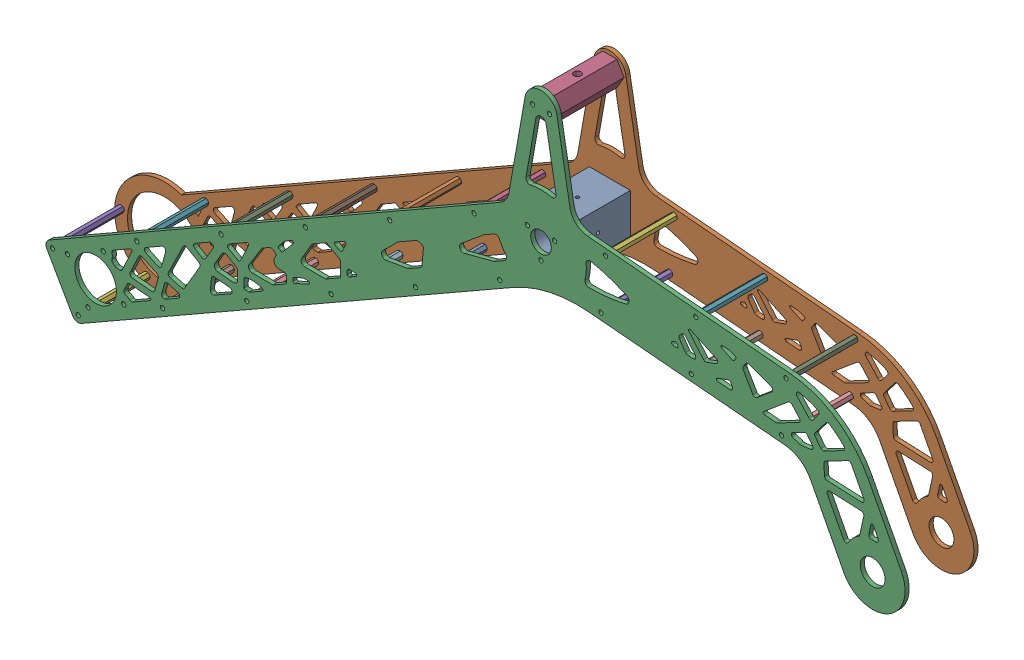
SolidWorks assembly Right Rocker Assy-2023, configuration Default. Lengths in mm.
Overall size (663.55 336.79 56.35).
22 component instances, 5 part files, 84 mates.
Components (placement in the parent):
- Rocker Adapter-2023-1: Rocker Adapter-2023 [Default] at origin size (31.75 31.75 50)
- Rocker Plate - Inner-2023-1: Rocker Plate - Inner-2023 [Default] at (0 0 -28.175) size (663.55 336.79 3.17)
- Rocker Plate - Outer-2023-1: Rocker Plate - Outer-2023 [Default] at (0 0 25) size (663.31 333.98 3.17)
- Differential Adapter-2023-1: Differential Adapter-2023 [Default] at (0 88.9125 0) size (21.94 19 50)
- Standoff Nut-2023-1: Standoff Nut-2023 [95947A502] at (-377.2333 -192.8465 -25) x (0 0 1) z (-1 0 0) size (50 4.5 5.2)
- Standoff Nut-2023-2: Standoff Nut-2023 [95947A502] at (-357.3649 -227.5632 -25) x (0 0 1) z (-0.987351 -0.158553 0) size (50 4.5 5.2)
- Standoff Nut-2023-3: Standoff Nut-2023 [95947A502] at (-312.1394 -155.5934 -25) x (0 0 1) z (-0.959125 -0.282984 0) size (50 4.5 5.2)
- Standoff Nut-2023-4: Standoff Nut-2023 [95947A502] at (-292.2711 -190.3101 -25) x (0 0 1) z (-0.928571 -0.371154 0) size (50 4.5 5.2)
- Standoff Nut-2023-5: Standoff Nut-2023 [95947A502] at (-247.0456 -118.3403 -25) x (0 0 1) z (-0.906989 -0.421154 0) size (50 4.5 5.2)
- Standoff Nut-2023-6: Standoff Nut-2023 [95947A502] at (-227.1773 -153.057 -25) x (0 0 1) z (-0.902849 -0.429957 0) size (50 4.5 5.2)
- Standoff Nut-2023-7: Standoff Nut-2023 [95947A502] at (-181.9518 -81.0871 -25) x (0 0 1) z (-0.919615 -0.39282 0) size (50 4.5 5.2)
- Standoff Nut-2023-8: Standoff Nut-2023 [95947A502] at (-162.0835 -115.8038 -25) x (0 0 1) z (-0.952324 -0.305088 0) size (50 4.5 5.2)
- Standoff Nut-2023-9: Standoff Nut-2023 [95947A502] at (-96.9897 -78.5507 -25) x (0 0 1) z (-0.985697 -0.168526 0) size (50 4.5 5.2)
- Standoff Nut-2023-10: Standoff Nut-2023 [95947A502] at (-116.858 -43.834 -25) x (0 0 1) z (-1 0 0) size (50 4.5 5.2)
- Standoff Nut-2023-11: Standoff Nut-2023 [95947A502] at (-31.8958 -41.2976 -25) x (0 0 1) z (-0.985697 0.168526 0) size (50 4.5 5.2)
- Standoff Nut-2023-12: Standoff Nut-2023 [95947A502] at (-51.7642 -6.5809 -25) x (0 0 1) z (-0.952324 0.305088 0) size (50 4.5 5.2)
- Standoff Nut-2023-13: Standoff Nut-2023 [95947A502] at (46.2693 -24.1244 -25) x (0 0 1) z (-0.919615 0.39282 0) size (50 4.5 5.2)
- Standoff Nut-2023-14: Standoff Nut-2023 [95947A502] at (49.7555 15.7234 -25) x (0 0 1) z (-0.902849 0.429957 0) size (50 4.5 5.2)
- Standoff Nut-2023-15: Standoff Nut-2023 [95947A502] at (119.4892 9.6224 -25) x (0 0 1) z (-0.906989 0.421154 0) size (50 4.5 5.2)
- Standoff Nut-2023-16: Standoff Nut-2023 [95947A502] at (116.0029 -30.2253 -25) x (0 0 1) z (-0.928571 0.371154 0) size (50 4.5 5.2)
- Standoff Nut-2023-17: Standoff Nut-2023 [95947A502] at (189.2228 3.5215 -25) x (0 0 1) z (-0.959125 0.282984 0) size (50 4.5 5.2)
- Standoff Nut-2023-18: Standoff Nut-2023 [95947A502] at (185.7366 -36.3262 -25) x (0 0 1) z (-0.987351 0.158553 0) size (50 4.5 5.2)
Mates (geometry in assembly coordinates):
- Concentric1: concentric anti-aligned: cylinder of Rocker Adapter-1 through (0 -12.1244 25) axis (0 0 -1) radius 1.25; cylinder of Rocker Plate - Inner-1 through (0 -12.1244 -28.175) axis (0 0 1) radius 1.65
- Concentric2: concentric anti-aligned: cylinder of Rocker Adapter-1 through (10.5 6.0622 25) axis (0 0 -1) radius 1.25; cylinder of Rocker Plate - Inner-1 through (10.5 6.0622 -28.175) axis (0 0 1) radius 1.65
- Coincident1: coincident anti-aligned: plane of Rocker Adapter-1 through (0 0 25) normal (0 0 1); plane of Rocker Plate - Outer-1 through (37.0941 36.9075 25) normal (0 0 -1)
- Concentric3: concentric anti-aligned: cylinder of Rocker Adapter-1 through (0 -12.1244 25) axis (0 0 -1) radius 1.25; cylinder of Rocker Plate - Outer-1 through (0 -12.1244 25) axis (0 0 1) radius 1.65
- Concentric4: concentric anti-aligned: cylinder of Rocker Adapter-1 through (-10.5 6.0622 25) axis (0 0 -1) radius 1.25; cylinder of Rocker Plate - Outer-1 through (-10.5 6.0622 25) axis (0 0 1) radius 1.65
- Coincident2: coincident anti-aligned: plane of Rocker Adapter-1 through (0 0 -25) normal (0 0 -1); plane of Rocker Plate - Inner-1 through (37.0941 36.9075 -25) normal (0 0 1)
- Concentric5: concentric aligned: cylinder of Rocker Plate - Outer-1 through (-6.5 88.9125 28.175) axis (0 0 -1) radius 1.65; cylinder of Differential Adapter-1 through (-6.5 88.9125 25) axis (0 0 -1) radius 1.25
- Concentric6: concentric aligned: cylinder of Rocker Plate - Outer-1 through (6.5 88.9125 28.175) axis (0 0 -1) radius 1.65; cylinder of Differential Adapter-1 through (6.5 88.9125 25) axis (0 0 -1) radius 1.25
- Concentric7: concentric aligned: cylinder of Rocker Plate - Inner-1 through (-6.5 88.9125 -25) axis (0 0 -1) radius 1.65; cylinder of Differential Adapter-1 through (-6.5 88.9125 25) axis (0 0 -1) radius 1.25
- Concentric8: concentric aligned: cylinder of Rocker Plate - Inner-1 through (6.5 88.9125 -25) axis (0 0 -1) radius 1.65; cylinder of Differential Adapter-1 through (6.5 88.9125 25) axis (0 0 -1) radius 1.25
- Coincident3: coincident anti-aligned: plane of Rocker Plate - Outer-1 through (37.0941 36.9075 25) normal (0 0 -1); plane of Differential Adapter-1 through (0 88.9125 25) normal (0 0 1)
- Coincident4: coincident anti-aligned: plane of Rocker Plate - Inner-1 through (37.0941 36.9075 -25) normal (0 0 1); plane of Differential Adapter-1 through (0 88.9125 -25) normal (0 0 -1)
- Concentric9: concentric anti-aligned: cylinder of Rocker Plate - Outer-1 through (-377.2333 -192.8465 25) axis (0 0 1) radius 1.65; cylinder of Standoff Nut-1 through (-377.2333 -192.8465 -25) axis (0 0 -1) radius 1.5
- Concentric10: concentric anti-aligned: cylinder of Rocker Plate - Inner-1 through (-377.2333 -192.8465 -28.175) axis (0 0 1) radius 1.65; cylinder of Standoff Nut-1 through (-377.2333 -192.8465 -25) axis (0 0 -1) radius 1.5
- Coincident5: coincident anti-aligned: plane of Rocker Plate - Outer-1 through (37.0941 36.9075 25) normal (0 0 -1); plane of Standoff Nut-1 through (-377.2333 -192.8465 25) normal (0 0 1)
- Coincident6: coincident anti-aligned: plane of Rocker Plate - Inner-1 through (37.0941 36.9075 -25) normal (0 0 1); plane of Standoff Nut-1 through (-377.2333 -192.8465 -25) normal (0 0 -1)
- Coincident7: coincident anti-aligned: plane of Rocker Plate - Outer-1 through (37.0941 36.9075 25) normal (0 0 -1); plane of Standoff Nut-2 through (-357.3649 -227.5632 25) normal (0 0 1)
- Coincident8: coincident anti-aligned: plane of Rocker Plate - Inner-1 through (37.0941 36.9075 -25) normal (0 0 1); plane of Standoff Nut-2 through (-357.3649 -227.5632 -25) normal (0 0 -1)
- Concentric11: concentric anti-aligned: cylinder of Rocker Plate - Outer-1 through (-357.3649 -227.5632 25) axis (0 0 1) radius 1.65; cylinder of Standoff Nut-2 through (-357.3649 -227.5632 -25) axis (0 0 -1) radius 1.5
- Concentric12: concentric anti-aligned: cylinder of Rocker Plate - Inner-1 through (-357.3649 -227.5632 -28.175) axis (0 0 1) radius 1.65; cylinder of Standoff Nut-2 through (-357.3649 -227.5632 -25) axis (0 0 -1) radius 1.5
- Coincident9: coincident anti-aligned: plane of Rocker Plate - Outer-1 through (37.0941 36.9075 25) normal (0 0 -1); plane of Standoff Nut-3 through (-312.1394 -155.5934 25) normal (0 0 1)
- Coincident10: coincident anti-aligned: plane of Rocker Plate - Inner-1 through (37.0941 36.9075 -25) normal (0 0 1); plane of Standoff Nut-3 through (-312.1394 -155.5934 -25) normal (0 0 -1)
- Concentric14: concentric anti-aligned: cylinder of Rocker Plate - Outer-1 through (-312.1394 -155.5934 25) axis (0 0 1) radius 1.65; cylinder of Standoff Nut-3 through (-312.1394 -155.5934 -25) axis (0 0 -1) radius 1.5
- Concentric15: concentric anti-aligned: cylinder of Rocker Plate - Inner-1 through (-312.1394 -155.5934 -28.175) axis (0 0 1) radius 1.65; cylinder of Standoff Nut-3 through (-312.1394 -155.5934 -25) axis (0 0 -1) radius 1.5
- Coincident11: coincident anti-aligned: plane of Rocker Plate - Outer-1 through (37.0941 36.9075 25) normal (0 0 -1); plane of Standoff Nut-4 through (-292.2711 -190.3101 25) normal (0 0 1)
- Coincident12: coincident anti-aligned: plane of Rocker Plate - Inner-1 through (37.0941 36.9075 -25) normal (0 0 1); plane of Standoff Nut-4 through (-292.2711 -190.3101 -25) normal (0 0 -1)
- Concentric16: concentric anti-aligned: cylinder of Rocker Plate - Outer-1 through (-292.2711 -190.3101 25) axis (0 0 1) radius 1.65; cylinder of Standoff Nut-4 through (-292.2711 -190.3101 -25) axis (0 0 -1) radius 1.5
- Concentric17: concentric anti-aligned: cylinder of Rocker Plate - Inner-1 through (-292.2711 -190.3101 -28.175) axis (0 0 1) radius 1.65; cylinder of Standoff Nut-4 through (-292.2711 -190.3101 -25) axis (0 0 -1) radius 1.5
- Coincident13: coincident anti-aligned: plane of Rocker Plate - Outer-1 through (37.0941 36.9075 25) normal (0 0 -1); plane of Standoff Nut-5 through (-247.0456 -118.3403 25) normal (0 0 1)
- Coincident14: coincident anti-aligned: plane of Rocker Plate - Inner-1 through (37.0941 36.9075 -25) normal (0 0 1); plane of Standoff Nut-5 through (-247.0456 -118.3403 -25) normal (0 0 -1)
- Concentric18: concentric anti-aligned: cylinder of Rocker Plate - Outer-1 through (-247.0456 -118.3403 25) axis (0 0 1) radius 1.65; cylinder of Standoff Nut-5 through (-247.0456 -118.3403 -25) axis (0 0 -1) radius 1.5
- Concentric19: concentric anti-aligned: cylinder of Rocker Plate - Inner-1 through (-247.0456 -118.3403 -28.175) axis (0 0 1) radius 1.65; cylinder of Standoff Nut-5 through (-247.0456 -118.3403 -25) axis (0 0 -1) radius 1.5
- Coincident15: coincident anti-aligned: plane of Rocker Plate - Outer-1 through (37.0941 36.9075 25) normal (0 0 -1); plane of Standoff Nut-6 through (-227.1773 -153.057 25) normal (0 0 1)
- Coincident16: coincident anti-aligned: plane of Rocker Plate - Inner-1 through (37.0941 36.9075 -25) normal (0 0 1); plane of Standoff Nut-6 through (-227.1773 -153.057 -25) normal (0 0 -1)
- Concentric20: concentric anti-aligned: cylinder of Rocker Plate - Outer-1 through (-227.1773 -153.057 25) axis (0 0 1) radius 1.65; cylinder of Standoff Nut-6 through (-227.1773 -153.057 -25) axis (0 0 -1) radius 1.5
- Concentric21: concentric anti-aligned: cylinder of Rocker Plate - Inner-1 through (-227.1773 -153.057 -28.175) axis (0 0 1) radius 1.65; cylinder of Standoff Nut-6 through (-227.1773 -153.057 -25) axis (0 0 -1) radius 1.5
- Coincident17: coincident anti-aligned: plane of Rocker Plate - Outer-1 through (37.0941 36.9075 25) normal (0 0 -1); plane of Standoff Nut-7 through (-181.9518 -81.0871 25) normal (0 0 1)
- Coincident18: coincident anti-aligned: plane of Rocker Plate - Inner-1 through (37.0941 36.9075 -25) normal (0 0 1); plane of Standoff Nut-7 through (-181.9518 -81.0871 -25) normal (0 0 -1)
- Concentric22: concentric anti-aligned: cylinder of Rocker Plate - Outer-1 through (-181.9518 -81.0871 25) axis (0 0 1) radius 1.65; cylinder of Standoff Nut-7 through (-181.9518 -81.0871 -25) axis (0 0 -1) radius 1.5
- Concentric23: concentric anti-aligned: cylinder of Rocker Plate - Inner-1 through (-181.9518 -81.0871 -28.175) axis (0 0 1) radius 1.65; cylinder of Standoff Nut-7 through (-181.9518 -81.0871 -25) axis (0 0 -1) radius 1.5
- Coincident19: coincident anti-aligned: plane of Rocker Plate - Outer-1 through (37.0941 36.9075 25) normal (0 0 -1); plane of Standoff Nut-8 through (-162.0835 -115.8038 25) normal (0 0 1)
- Coincident20: coincident anti-aligned: plane of Rocker Plate - Inner-1 through (37.0941 36.9075 -25) normal (0 0 1); plane of Standoff Nut-8 through (-162.0835 -115.8038 -25) normal (0 0 -1)
- Concentric24: concentric anti-aligned: cylinder of Rocker Plate - Outer-1 through (-162.0835 -115.8038 25) axis (0 0 1) radius 1.65; cylinder of Standoff Nut-8 through (-162.0835 -115.8038 -25) axis (0 0 -1) radius 1.5
- Concentric25: concentric anti-aligned: cylinder of Rocker Plate - Inner-1 through (-162.0835 -115.8038 -28.175) axis (0 0 1) radius 1.65; cylinder of Standoff Nut-8 through (-162.0835 -115.8038 -25) axis (0 0 -1) radius 1.5
- Coincident21: coincident anti-aligned: plane of Rocker Plate - Outer-1 through (37.0941 36.9075 25) normal (0 0 -1); plane of Standoff Nut-9 through (-96.9897 -78.5507 25) normal (0 0 1)
- Coincident22: coincident anti-aligned: plane of Rocker Plate - Inner-1 through (37.0941 36.9075 -25) normal (0 0 1); plane of Standoff Nut-9 through (-96.9897 -78.5507 -25) normal (0 0 -1)
- Concentric26: concentric anti-aligned: cylinder of Rocker Plate - Outer-1 through (-96.9897 -78.5507 25) axis (0 0 1) radius 1.65; cylinder of Standoff Nut-9 through (-96.9897 -78.5507 -25) axis (0 0 -1) radius 1.5
- Concentric27: concentric anti-aligned: cylinder of Rocker Plate - Inner-1 through (-96.9897 -78.5507 -28.175) axis (0 0 1) radius 1.65; cylinder of Standoff Nut-9 through (-96.9897 -78.5507 -25) axis (0 0 -1) radius 1.5
- Coincident23: coincident anti-aligned: plane of Rocker Plate - Outer-1 through (37.0941 36.9075 25) normal (0 0 -1); plane of Standoff Nut-10 through (-116.858 -43.834 25) normal (0 0 1)
- Coincident24: coincident anti-aligned: plane of Rocker Plate - Inner-1 through (37.0941 36.9075 -25) normal (0 0 1); plane of Standoff Nut-10 through (-116.858 -43.834 -25) normal (0 0 -1)
- Concentric28: concentric anti-aligned: cylinder of Rocker Plate - Outer-1 through (-116.858 -43.834 25) axis (0 0 1) radius 1.65; cylinder of Standoff Nut-10 through (-116.858 -43.834 -25) axis (0 0 -1) radius 1.5
- Concentric29: concentric anti-aligned: cylinder of Rocker Plate - Inner-1 through (-116.858 -43.834 -28.175) axis (0 0 1) radius 1.65; cylinder of Standoff Nut-10 through (-116.858 -43.834 -25) axis (0 0 -1) radius 1.5
- Coincident25: coincident anti-aligned: plane of Rocker Plate - Outer-1 through (37.0941 36.9075 25) normal (0 0 -1); plane of Standoff Nut-11 through (-31.8958 -41.2976 25) normal (0 0 1)
- Coincident26: coincident anti-aligned: plane of Rocker Plate - Inner-1 through (37.0941 36.9075 -25) normal (0 0 1); plane of Standoff Nut-11 through (-31.8958 -41.2976 -25) normal (0 0 -1)
- Concentric30: concentric anti-aligned: cylinder of Rocker Plate - Outer-1 through (-31.8958 -41.2976 25) axis (0 0 1) radius 1.65; cylinder of Standoff Nut-11 through (-31.8958 -41.2976 -25) axis (0 0 -1) radius 1.5
- Concentric31: concentric anti-aligned: cylinder of Rocker Plate - Inner-1 through (-31.8958 -41.2976 -28.175) axis (0 0 1) radius 1.65; cylinder of Standoff Nut-11 through (-31.8958 -41.2976 -25) axis (0 0 -1) radius 1.5
- Coincident27: coincident anti-aligned: plane of Rocker Plate - Outer-1 through (37.0941 36.9075 25) normal (0 0 -1); plane of Standoff Nut-12 through (-51.7642 -6.5809 25) normal (0 0 1)
- Coincident28: coincident anti-aligned: plane of Rocker Plate - Inner-1 through (37.0941 36.9075 -25) normal (0 0 1); plane of Standoff Nut-12 through (-51.7642 -6.5809 -25) normal (0 0 -1)
- Concentric32: concentric anti-aligned: cylinder of Rocker Plate - Outer-1 through (-51.7642 -6.5809 25) axis (0 0 1) radius 1.65; cylinder of Standoff Nut-12 through (-51.7642 -6.5809 -25) axis (0 0 -1) radius 1.5
- Concentric33: concentric anti-aligned: cylinder of Rocker Plate - Inner-1 through (-51.7642 -6.5809 -28.175) axis (0 0 1) radius 1.65; cylinder of Standoff Nut-12 through (-51.7642 -6.5809 -25) axis (0 0 -1) radius 1.5
- Coincident29: coincident anti-aligned: plane of Rocker Plate - Outer-1 through (37.0941 36.9075 25) normal (0 0 -1); plane of Standoff Nut-13 through (46.2693 -24.1244 25) normal (0 0 1)
- Coincident30: coincident anti-aligned: plane of Rocker Plate - Inner-1 through (37.0941 36.9075 -25) normal (0 0 1); plane of Standoff Nut-13 through (46.2693 -24.1244 -25) normal (0 0 -1)
- Concentric34: concentric anti-aligned: cylinder of Rocker Plate - Outer-1 through (46.2693 -24.1244 25) axis (0 0 1) radius 1.65; cylinder of Standoff Nut-13 through (46.2693 -24.1244 -25) axis (0 0 -1) radius 1.5
- Concentric35: concentric anti-aligned: cylinder of Rocker Plate - Inner-1 through (46.2693 -24.1244 -28.175) axis (0 0 1) radius 1.65; cylinder of Standoff Nut-13 through (46.2693 -24.1244 -25) axis (0 0 -1) radius 1.5
- Coincident31: coincident anti-aligned: plane of Rocker Plate - Outer-1 through (37.0941 36.9075 25) normal (0 0 -1); plane of Standoff Nut-14 through (49.7555 15.7234 25) normal (0 0 1)
- Coincident32: coincident anti-aligned: plane of Rocker Plate - Inner-1 through (37.0941 36.9075 -25) normal (0 0 1); plane of Standoff Nut-14 through (49.7555 15.7234 -25) normal (0 0 -1)
- Concentric36: concentric anti-aligned: cylinder of Rocker Plate - Outer-1 through (49.7555 15.7234 25) axis (0 0 1) radius 1.65; cylinder of Standoff Nut-14 through (49.7555 15.7234 -25) axis (0 0 -1) radius 1.5
- Concentric37: concentric anti-aligned: cylinder of Rocker Plate - Inner-1 through (49.7555 15.7234 -28.175) axis (0 0 1) radius 1.65; cylinder of Standoff Nut-14 through (49.7555 15.7234 -25) axis (0 0 -1) radius 1.5
- Coincident33: coincident anti-aligned: plane of Rocker Plate - Outer-1 through (37.0941 36.9075 25) normal (0 0 -1); plane of Standoff Nut-15 through (119.4892 9.6224 25) normal (0 0 1)
- Coincident34: coincident anti-aligned: plane of Rocker Plate - Inner-1 through (37.0941 36.9075 -25) normal (0 0 1); plane of Standoff Nut-15 through (119.4892 9.6224 -25) normal (0 0 -1)
- Concentric38: concentric anti-aligned: cylinder of Rocker Plate - Outer-1 through (119.4892 9.6224 25) axis (0 0 1) radius 1.65; cylinder of Standoff Nut-15 through (119.4892 9.6224 -25) axis (0 0 -1) radius 1.5
- Concentric39: concentric anti-aligned: cylinder of Rocker Plate - Inner-1 through (119.4892 9.6224 -28.175) axis (0 0 1) radius 1.65; cylinder of Standoff Nut-15 through (119.4892 9.6224 -25) axis (0 0 -1) radius 1.5
- Coincident35: coincident anti-aligned: plane of Rocker Plate - Outer-1 through (37.0941 36.9075 25) normal (0 0 -1); plane of Standoff Nut-16 through (116.0029 -30.2253 25) normal (0 0 1)
- Coincident36: coincident anti-aligned: plane of Rocker Plate - Inner-1 through (37.0941 36.9075 -25) normal (0 0 1); plane of Standoff Nut-16 through (116.0029 -30.2253 -25) normal (0 0 -1)
- Concentric40: concentric anti-aligned: cylinder of Rocker Plate - Outer-1 through (116.0029 -30.2253 25) axis (0 0 1) radius 1.65; cylinder of Standoff Nut-16 through (116.0029 -30.2253 -25) axis (0 0 -1) radius 1.5
- Concentric41: concentric anti-aligned: cylinder of Rocker Plate - Inner-1 through (116.0029 -30.2253 -28.175) axis (0 0 1) radius 1.65; cylinder of Standoff Nut-16 through (116.0029 -30.2253 -25) axis (0 0 -1) radius 1.5
- Coincident37: coincident anti-aligned: plane of Rocker Plate - Outer-1 through (37.0941 36.9075 25) normal (0 0 -1); plane of Standoff Nut-17 through (189.2228 3.5215 25) normal (0 0 1)
- Coincident38: coincident anti-aligned: plane of Rocker Plate - Inner-1 through (37.0941 36.9075 -25) normal (0 0 1); plane of Standoff Nut-17 through (189.2228 3.5215 -25) normal (0 0 -1)
- Concentric42: concentric anti-aligned: cylinder of Rocker Plate - Outer-1 through (189.2228 3.5215 25) axis (0 0 1) radius 1.65; cylinder of Standoff Nut-17 through (189.2228 3.5215 -25) axis (0 0 -1) radius 1.5
- Concentric43: concentric anti-aligned: cylinder of Rocker Plate - Inner-1 through (189.2228 3.5215 -28.175) axis (0 0 1) radius 1.65; cylinder of Standoff Nut-17 through (189.2228 3.5215 -25) axis (0 0 -1) radius 1.5
- Coincident39: coincident anti-aligned: plane of Rocker Plate - Outer-1 through (37.0941 36.9075 25) normal (0 0 -1); plane of Standoff Nut-18 through (185.7366 -36.3262 25) normal (0 0 1)
- Coincident40: coincident anti-aligned: plane of Rocker Plate - Inner-1 through (37.0941 36.9075 -25) normal (0 0 1); plane of Standoff Nut-18 through (185.7366 -36.3262 -25) normal (0 0 -1)
- Concentric44: concentric anti-aligned: cylinder of Rocker Plate - Outer-1 through (185.7366 -36.3262 25) axis (0 0 1) radius 1.65; cylinder of Standoff Nut-18 through (185.7366 -36.3262 -25) axis (0 0 -1) radius 1.5
- Concentric45: concentric anti-aligned: cylinder of Rocker Plate - Inner-1 through (185.7366 -36.3262 -28.175) axis (0 0 1) radius 1.65; cylinder of Standoff Nut-18 through (185.7366 -36.3262 -25) axis (0 0 -1) radius 1.5
